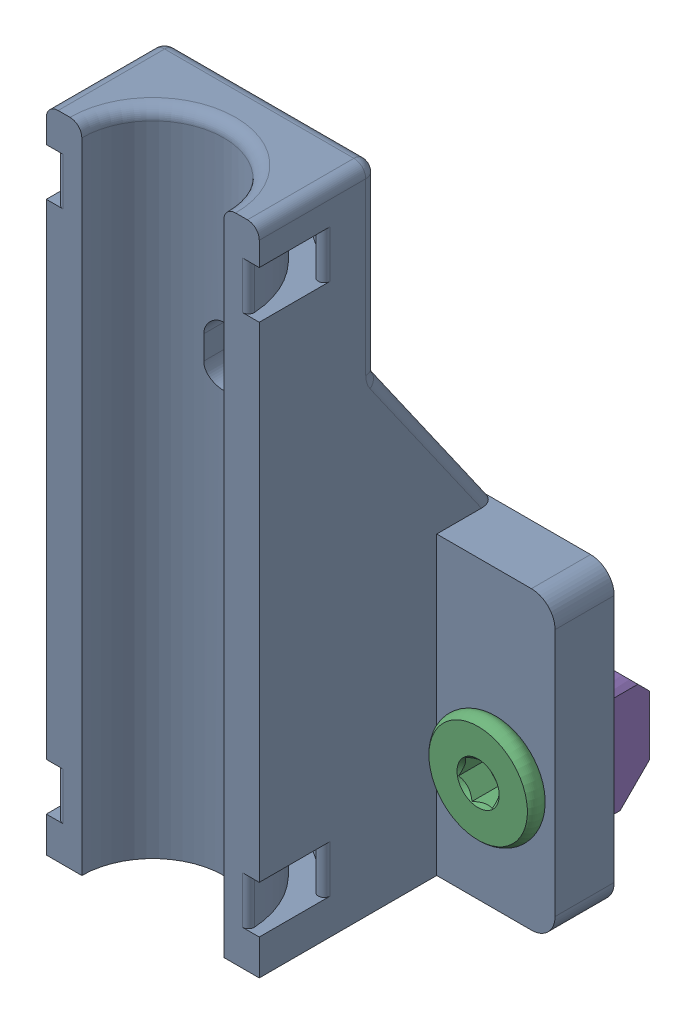
SolidWorks assembly tool_cable_management_assembly_2, configuration Default. Lengths in mm.
Overall size (40.2 55.06 25).
5 component instances, 3 part files, 0 mates.
Components (placement in the parent):
- tool_cable_management_bracket-1: tool_cable_management_bracket [Default] at (1.9041 354.0105 503.3157) x (-1 0 0) z (0 0 -1) size (38 55.06 20)
- m5_low_profile_screw_template_M5 x 10-1: m5_low_profile_screw_template_M5 x 10 [Default] at (-12.0959 364.0105 498.3157) x (0 0 -1) z (0.928561 0.37118 0) size (11.62 9 9)
- m5_low_profile_screw_template_M5 x 10-2: m5_low_profile_screw_template_M5 x 10 [Default] at (15.9041 364.0105 498.3157) x (0 0 -1) z (0.757132 0.653262 0) size (11.62 9 9)
- m5_locking_t_nut_20x20_generic-1: m5_locking_t_nut_20x20_generic [Default] at (-9.0959 364.0105 498.3157) x (0 -1 0) z (-1 0 0) size (10 4.5 6)
- m5_locking_t_nut_20x20_generic-2: m5_locking_t_nut_20x20_generic [Default] at (18.9041 364.0105 498.3157) x (0 -1 0) z (-1 0 0) size (10 4.5 6)
